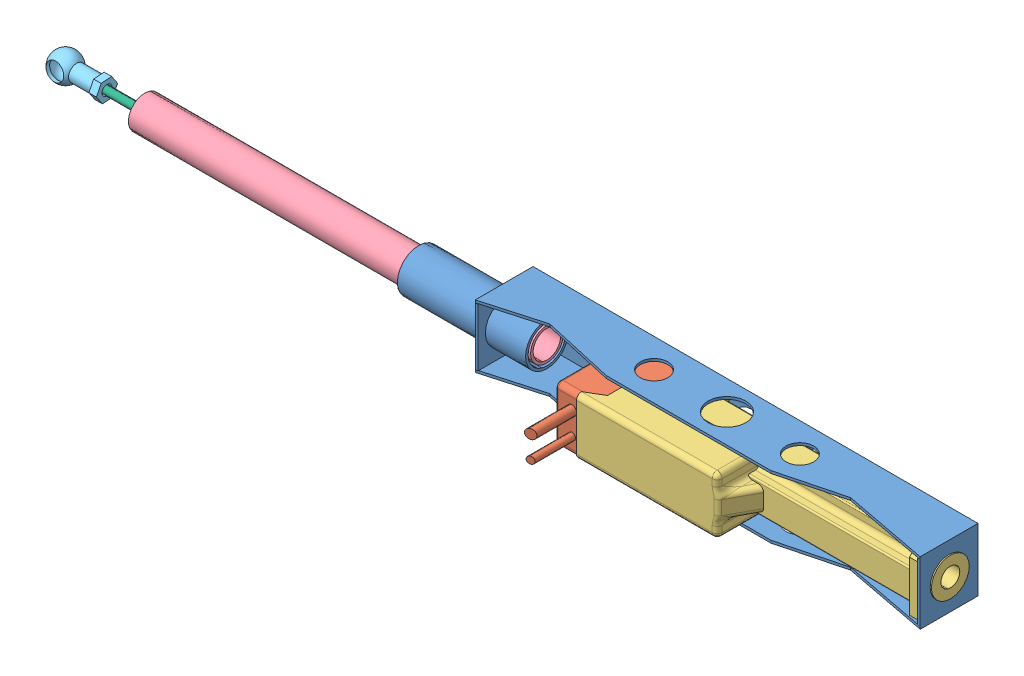
SolidWorks assembly verin, configuration Défaut. Lengths in mm.
Overall size (715 50 102.68).
7 component instances, 6 part files, 9 mates.
Components (placement in the parent):
- support_verin-1: support_verin [Défaut] at origin size (422 50 46)
- corps_verin-1: corps_verin [Défaut] at (53.4998 119.4835 -2.1976) x (0 1 0) z (1 0 0) size (45 102.68 269)
  - RSA04-1: RSA04 [Défaut] at (-95.9835 24.6976 97.5002) size (44 102.68 87.5)
  - prt-SCN5-150-2: prt-SCN5-150 [Défaut] at (-96.4835 25.1976 97.5002) size (45 68.14 252)
- extension_tige-1: extension_tige [Défaut] at (32 23 23) x (0 -0.760787 -0.649002) z (-1 0 0) size (26 26 320)
- joint_rotule_femelle-1: joint_rotule_femelle [Défaut] at (-351 23 23) x (0 0.07072 0.997496) z (1 0 0) size (19.49 22 44)
- tige_filetee-1: tige_filetee [Défaut] at (-172 23 23) x (0 -0.855363 -0.518028) z (0 0.518028 -0.855363) size (6 152 6)
Mates (geometry in assembly coordinates):
- Coaxiale1: concentric aligned: cylinder of support_verin-1; cylinder of extension_tige-1
- Coïncidente1: coincident anti-aligned: plane of support_verin-1 through (0 0 0) normal (0 0 1); plane of corps_verin-1/prt-SCN5-150-2 through (350 23 23) normal (1 0 0)
- Coaxiale2: concentric anti-aligned: cylinder of support_verin-1; cylinder of corps_verin-1/prt-SCN5-150-2
- Parallèle1: parallel anti-aligned: plane of support_verin-1 through (-2 0 46) normal (0 1 0); plane of corps_verin-1/prt-SCN5-150-2 through (156 1.5 23) normal (0 -1 0)
- Coïncidente3: coincident aligned: plane of support_verin-1 through (32 23 23) normal (1 0 0); plane of extension_tige-1 through (32 23 23) normal (1 0 0)
- Coaxiale3: concentric aligned: cylinder of extension_tige-1; cylinder of tige_filetee-1
- Coaxiale4: concentric anti-aligned: cylinder of joint_rotule_femelle-1; cylinder of tige_filetee-1
- Coïncidente5: coincident aligned: plane of joint_rotule_femelle-1 through (-324 30.0107 27.693) normal (-1 0 0); plane of tige_filetee-1 through (-324 23 23) normal (-1 0 0)
- Distance1: distance = 30 mm anti-aligned: plane of joint_rotule_femelle-1 through (-318 30.0107 27.693) normal (1 0 0); plane of extension_tige-1 through (-288 23 23) normal (-1 0 0)
